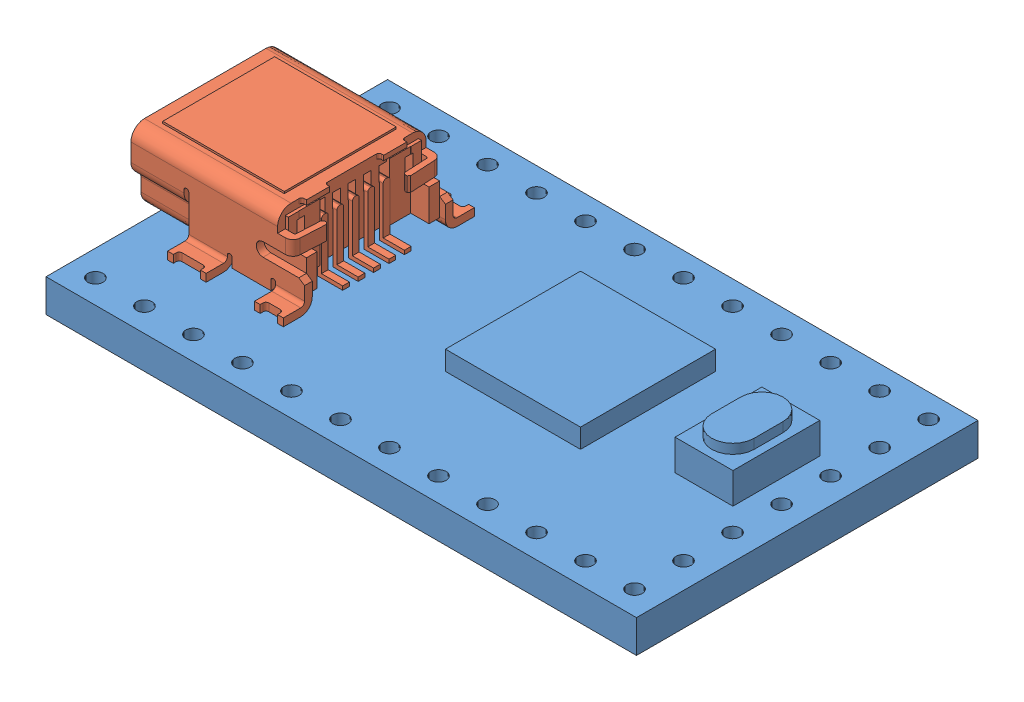
SolidWorks assembly Teensy 2.0 assy, configuration Défaut. Lengths in mm.
Overall size (31.2 5.75 17.7).
2 component instances, 2 part files, 3 mates.
Components (placement in the parent):
- teensy 2-1: teensy 2 [Défaut] at origin size (30.6 3.8 17.7)
- miniusb_pcb_smd-1: miniusb_pcb_smd [Défaut] at (-15.9 3.7 0) x (0 0 1) z (-1 0 0) size (9.9 4.05 9)
Mates (geometry in assembly coordinates):
- Coïncidente1: coincident anti-aligned: plane of teensy 2-1 through (0 1.7 0) normal (0 1 0); plane of miniusb_pcb_smd-1 through (-7.222 1.7 4.05) normal (0 -1 0)
- Coïncidente2: coincident aligned: plane of miniusb_pcb_smd-1 through (-15.9 3.7 0) normal (0 0 1); plane of assembly
- Distance1: distance = 0.6 mm aligned: plane of miniusb_pcb_smd-1 through (-15.9 3.7 0) normal (-1 0 0); plane of teensy 2-1 through (-15.3 1.7 -8.85) normal (-1 0 0)
